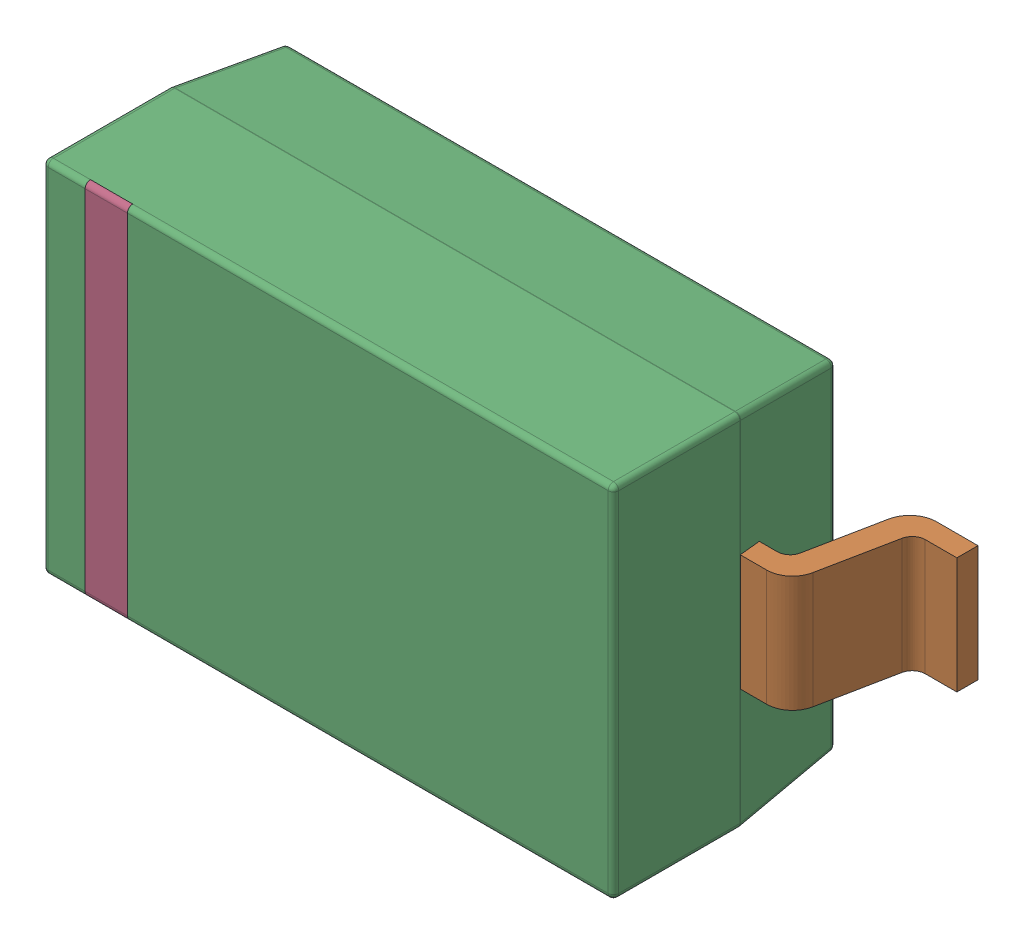
SolidWorks assembly D3, configuration Default. Lengths in mm.
Overall size (3.75 1.71 1.2).
5 component instances, 4 part files, 0 mates.
Components (placement in the parent):
- sod123_v4-1: sod123_v4 [Default] at (75.4701 2.3001 0) x (1 0 0) z (0 0 1) size (3.75 1.71 1.2)
  - pin-1: pin [Default] at (-0.675 -0.875 0) x (0 -1 0) z (0 0 1) size (0.55 0.55 0.6)
  - pin(Mirror)-1: pin(Mirror) [Default] at (0.675 -0.875 0) x (0 -1 0) z (0 0 -1) size (0.55 0.55 0.6)
  - icbody-1: icbody [Default] at origin size (2.71 1.71 1.11)
  - Component5-1: Component5 [Default] at origin size (0.2 1.7 0.02)
